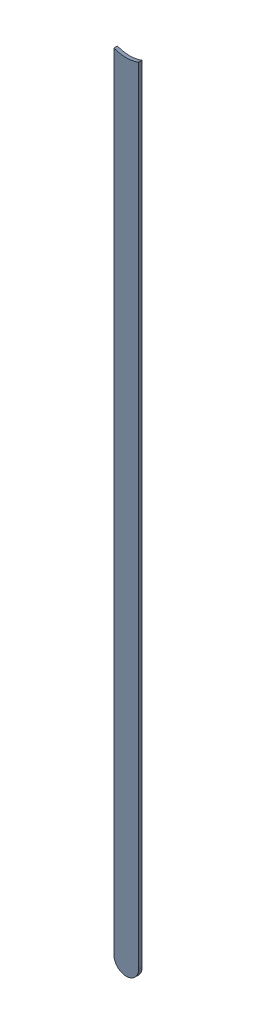
SolidWorks assembly Track (26.1mm,48.6mm)(26.1mm,57mm) on Bottom Layer, configuration Predeterminado. Lengths in mm.
Overall size (0.25 8.2 0.04).
2 component instances, 1 part files, 0 mates.
Components (placement in the parent):
- Track (26.1mm,48.6mm)(26.1mm,57mm) on Bottom Layer-1-1: Track (26.1mm,48.6mm)(26.1mm,57mm) on Bottom Layer-1 [Predeterminado] at (-68.317 -44.187 -0.4013) size (0.25 8.2 0.04)
  - Track (26.1mm,48.6mm)(26.1mm,57mm) on Bottom Layer-Part-1-1: Track (26.1mm,48.6mm)(26.1mm,57mm) on Bottom Layer-Part-1 [Predeterminado] at origin size (0.25 8.2 0.04)
